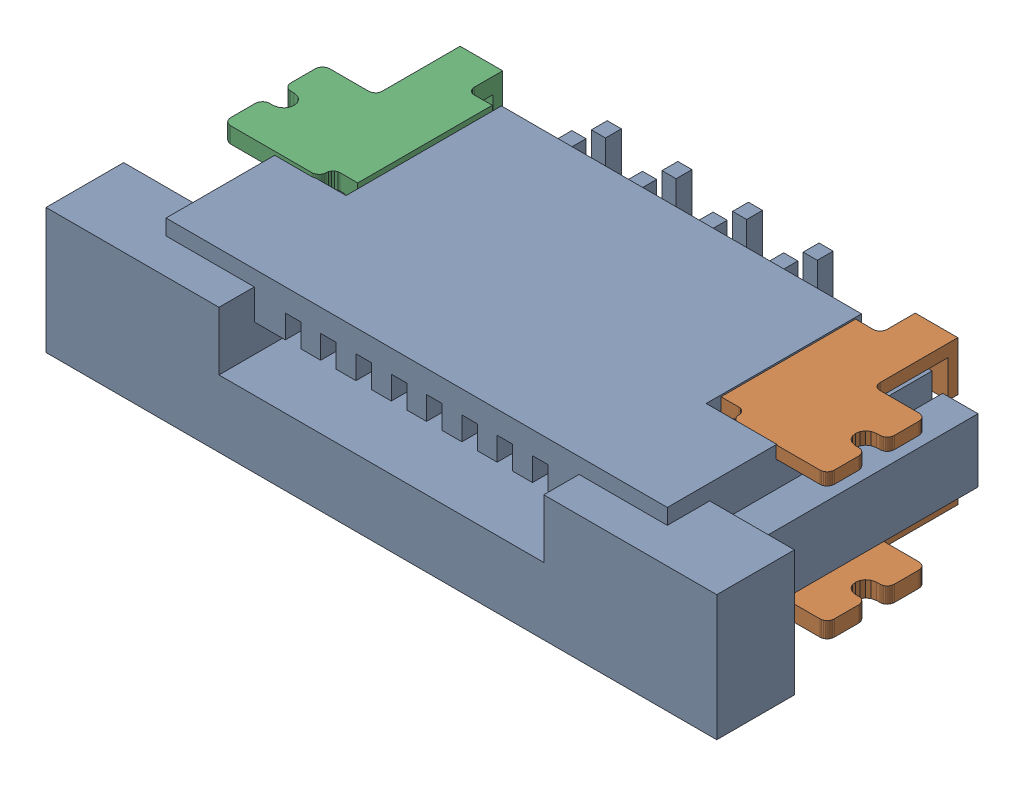
SolidWorks assembly P5主板_V1.0, configuration 默认. Lengths in mm.
Overall size (9.5 2.54 4.64).
4 component instances, 3 part files, 0 mates.
Components (placement in the parent):
- Header-FPC-ZIF-SMD-Vertical_Single-0.5-8-1: Header-FPC-ZIF-SMD-Vertical_Single-0.5-8 [默认] at (73.6202 47.7766 4.08) x (-1 0 0) z (0 0 1) size (9.5 2.54 4.64)
  - ffc_fpc_affc20-08-050-shb-t_01-1: ffc_fpc_affc20-08-050-shb-t_01 [默认] at origin size (9.5 2.54 4.55)
  - ffc_fpc_affc20-08-050-shb-t_02-1: ffc_fpc_affc20-08-050-shb-t_02 [默认] at origin size (1.7 2.05 2.6)
  - ffc_fpc_affc20-08-050-shb-t_03-1: ffc_fpc_affc20-08-050-shb-t_03 [默认] at origin size (1.7 2.05 2.6)
